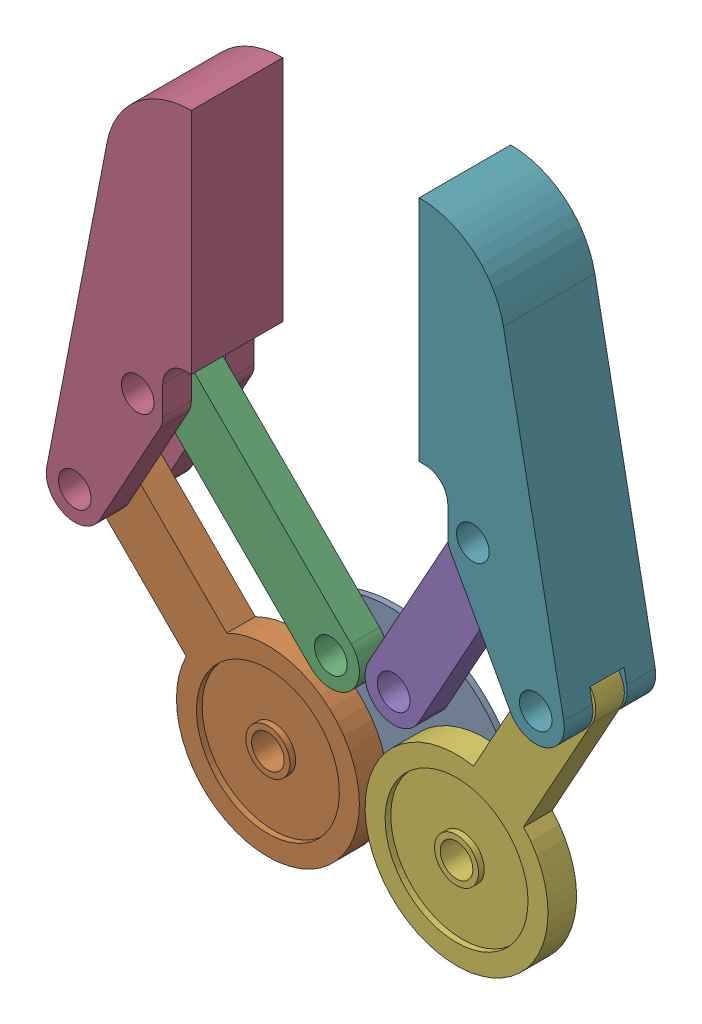
SolidWorks assembly Claw1 Q8, configuration Default. Lengths in mm.
Overall size (111.91 125.22 16).
7 component instances, 4 part files, 18 mates.
Components (placement in the parent):
- Arm_Plate-1: Arm_Plate [Default] at (16.3184 9.8304 30.4902) x (0 -1 0) z (0 0 1) size (32.5 45 1)
- Arm_Gear-1: Arm_Gear [Default] at (-14.3238 23.9725 33.9902) x (0.707107 -0.707107 0) z (0 0 1) size (61 32 5)
- Arm_Link-1: Arm_Link [Default] at (-3.3238 43.9725 33.9902) x (0.707107 -0.707107 0) z (0 0 1) size (50 10 5)
- Grip-1: Grip [Default] at (-8.0848 105.7051 41.9902) x (0 -1 0) z (0 0 -1) size (72.59 25.38 16)
- Arm_Link-2: Arm_Link [Default] at (31.4948 47.3338 33.9902) x (-0.483819 -0.875168 0) z (0 0 1) size (50 10 5)
- Arm_Gear-2: Arm_Gear [Default] at (42.4948 27.3338 33.9902) x (-0.483819 -0.875168 0) z (0 0 1) size (61 32 5)
- Grip-2: Grip [Default] at (31.79 112.4275 25.9902) x (0 -1 0) z (0 0 1) size (72.59 25.38 16)
Mates (geometry in assembly coordinates):
- Coincident8: coincident anti-aligned: plane of Arm_Plate-1 through (16.3184 14.8304 31.4902) normal (0 0 1); plane of Arm_Gear-1 through (-28.4659 38.1147 31.4902) normal (0 0 -1)
- Coincident9: coincident anti-aligned: plane of Arm_Plate-1 through (16.3184 14.8304 31.4902) normal (0 0 1); plane of Arm_Gear-2 through (52.1711 44.8371 31.4902) normal (0 0 -1)
- Concentric10: concentric aligned: cylinder of Arm_Plate-1 through (32.8184 9.8304 31.4902) axis (0 0 -1) radius 2.85; cylinder of Arm_Gear-2 through (32.8184 9.8304 36.4902) axis (0 0 -1) radius 2.85
- Concentric11: concentric aligned: cylinder of Arm_Plate-1 through (-0.1816 9.8304 31.4902) axis (0 0 -1) radius 2.85; cylinder of Arm_Gear-1 through (-0.1816 9.8304 36.4902) axis (0 0 -1) radius 2.85
- Concentric12: concentric aligned: cylinder of Arm_Plate-1 through (10.8184 29.8304 31.4902) axis (0 0 -1) radius 2.85; cylinder of Arm_Link-1 through (10.8184 29.8304 36.4902) axis (0 0 -1) radius 2.85
- Coincident11: coincident anti-aligned: plane of Arm_Plate-1 through (16.3184 14.8304 31.4902) normal (0 0 1); plane of Arm_Link-1 through (-17.4659 58.1147 31.4902) normal (0 0 -1)
- Concentric13: concentric aligned: cylinder of Arm_Plate-1 through (21.8184 29.8304 31.4902) axis (0 0 -1) radius 2.85; cylinder of Arm_Link-2 through (21.8184 29.8304 36.4902) axis (0 0 -1) radius 2.85
- Coincident12: coincident anti-aligned: plane of Arm_Plate-1 through (16.3184 14.8304 31.4902) normal (0 0 1); plane of Arm_Link-2 through (41.1711 64.8371 31.4902) normal (0 0 -1)
- Width3: width anti-aligned: plane of Arm_Link-1 through (-17.4659 58.1147 36.4902) normal (0 0 1); plane of Arm_Link-1 through (-17.4659 58.1147 31.4902) normal (0 0 -1); plane of Grip-1 through (-9.0848 61.7051 36.9902) normal (0 0 -1); plane of Grip-1 through (-70.8921 33.1147 30.9902) normal (0 0 1)
- Concentric14: concentric anti-aligned: cylinder of Arm_Gear-1 through (-28.4659 38.1147 36.4902) axis (0 0 -1) radius 2.85; cylinder of Grip-1 through (-28.4659 38.1147 36.9902) axis (0 0 1) radius 2.85
- Concentric15: concentric anti-aligned: cylinder of Arm_Link-1 through (-17.4659 58.1147 36.4902) axis (0 0 -1) radius 2.85; cylinder of Grip-1 through (-17.4659 58.1147 36.9902) axis (0 0 1) radius 2.85
- Width4: width aligned: plane of Arm_Gear-2 through (52.1711 44.8371 36.4902) normal (0 0 1); plane of Arm_Gear-2 through (52.1711 44.8371 31.4902) normal (0 0 -1); plane of Grip-2 through (32.79 68.4275 30.9902) normal (0 0 1); plane of Grip-2 through (94.5973 39.8371 36.9902) normal (0 0 -1)
- Concentric16: concentric aligned: cylinder of Arm_Gear-2 through (52.1711 44.8371 36.4902) axis (0 0 -1) radius 2.85; cylinder of Grip-2 through (52.1711 44.8371 41.9902) axis (0 0 -1) radius 2.85
- Concentric17: concentric aligned: cylinder of Arm_Link-2 through (41.1711 64.8371 36.4902) axis (0 0 -1) radius 2.85; cylinder of Grip-2 through (41.1711 64.8371 41.9902) axis (0 0 -1) radius 2.85
- Coincident13: coincident anti-aligned: plane of Grip-1 through (-8.0848 105.7051 25.9902) normal (1 0 0); plane of Grip-2 through (31.79 112.4275 41.9902) normal (-1 0 0)
- Coincident14: coincident anti-aligned: line of Grip-1 through (-8.0848 65.7051 25.9902) axis (0 0 1); line of Grip-2 through (31.79 72.4275 41.9902) axis (0 0 -1)
- GearMate1: gear = 54 : 32 mm: cylinder of Arm_Gear-1 through (-0.1816 9.8304 36.4902) axis (0 0 -1) radius 16; cylinder of Arm_Gear-2 through (32.8184 9.8304 36.4902) axis (0 0 -1) radius 16
- Angle2: planar angle = 0.785398 rad aligned: plane of Arm_Gear-1 through (-32.0014 34.5791 36.4902) normal (-0.707107 -0.707107 0); plane of Arm_Plate-1 through (-6.1816 4.8304 31.4902) normal (0 -1 0)
